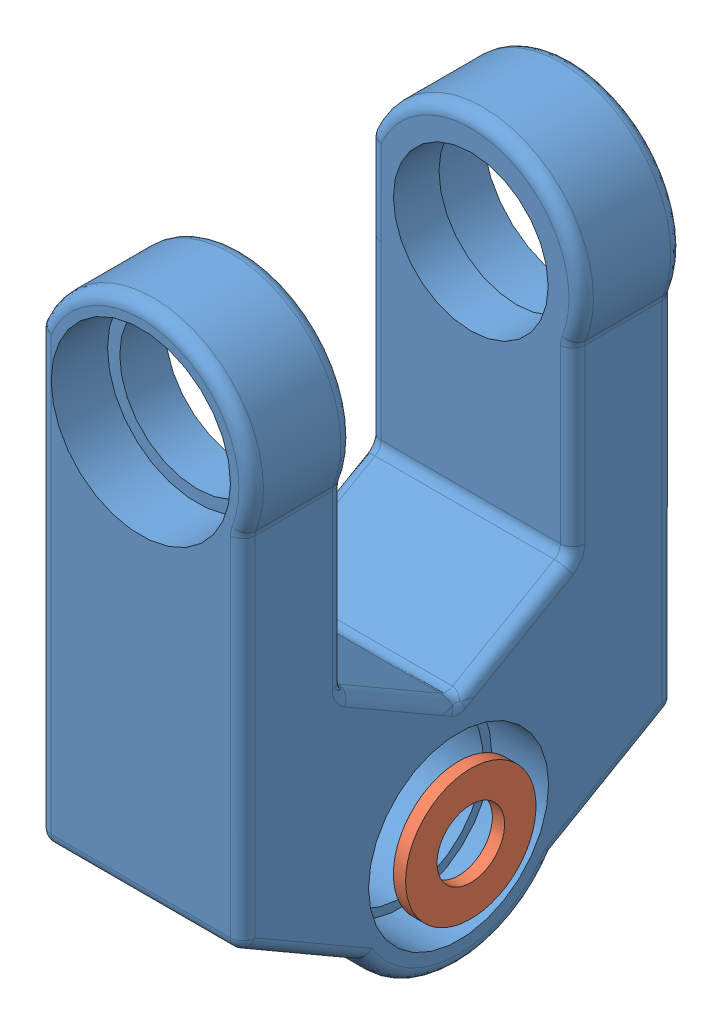
SolidWorks assembly HUB TOP, configuration Default. Lengths in mm.
Overall size (28 77.55 53).
3 component instances, 2 part files, 4 mates.
Components (placement in the parent):
- HUB TOP-1: HUB TOP [Default] at (-3.1766 3.4465 0) size (26.28 77.55 53)
- M8 WASHER_1-1: M8 WASHER_1 [Default] at (10.8234 -46.5535 14) x (0 0 1) z (-1 0 0) size (16 16 1.5)
- M8 WASHER_1-2: M8 WASHER_1 [Default] at (-15.6766 -46.5535 14) x (0 0 1) z (-1 0 0) size (16 16 1.5)
Mates (geometry in assembly coordinates):
- Concentric1: concentric aligned: cylinder of HUB TOP-1 through (-8.6766 -46.5535 14) axis (-1 0 0) radius 11.05; cylinder of M8 WASHER_1-2 through (-15.6766 -46.5535 14) axis (-1 0 0) radius 8
- Coincident1: coincident anti-aligned: plane of HUB TOP-1 through (-15.6766 -26.6423 -4.5097) normal (-1 0 0); plane of M8 WASHER_1-2 through (-15.6766 -46.5535 14) normal (1 0 0)
- Concentric5: concentric anti-aligned: cylinder of HUB TOP-1 through (2.3234 -46.5535 14) axis (1 0 0) radius 11.05; cylinder of M8 WASHER_1-1 through (10.8234 -46.5535 14) axis (-1 0 0) radius 8
- Coincident4: coincident anti-aligned: plane of HUB TOP-1 through (9.3234 -26.6423 -4.5097) normal (1 0 0); plane of M8 WASHER_1-1 through (9.3234 -46.5535 14) normal (-1 0 0)
